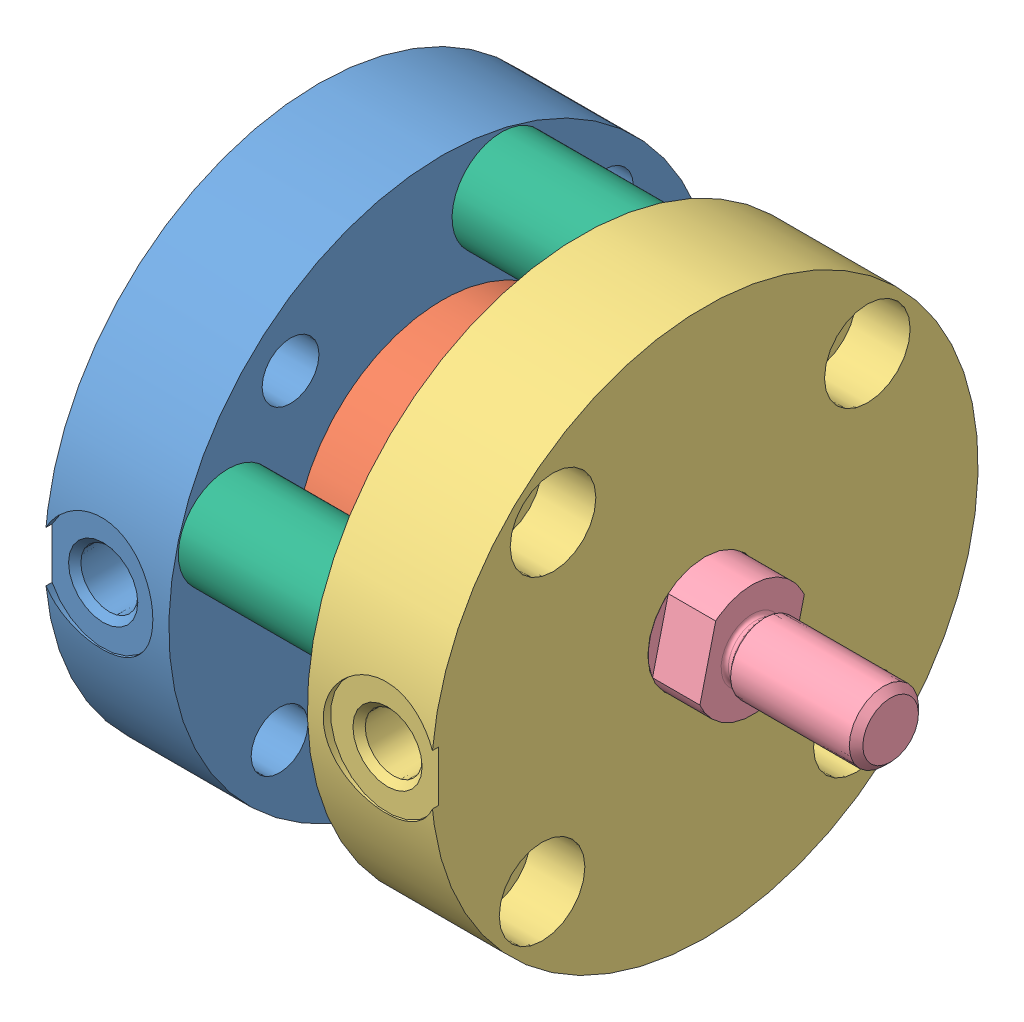
SolidWorks assembly FO-040.5-MT, configuration Default. Lengths in mm.
Overall size (40.11 38.1 38.1).
9 component instances, 6 part files, 2 mates.
Components (placement in the parent):
- _04-2-0.51-FO1_BM_heads-1: _04-2-0.51-FO1_BM_heads [Default] at (8.636 0 0) x (0 0 -1) z (0 1 0) size (38.1 8.87 38.1)
- _040.72-FO1_BM_tube-1: _040.72-FO1_BM_tube [Default] at (4.318 0 0) x (0 0 -1) z (0 -1 0) size (20.62 18.29 20.62)
- _04-1-0.51-FO1_BM_heads-1: _04-1-0.51-FO1_BM_heads [Default] at (18.288 0 0) x (0 0 -1) z (0 -1 0) size (38.1 8.87 38.1)
- _041.41.4MT-FO1_BM_rod-1: _041.41.4MT-FO1_BM_rod [Default] at (4.318 0 0) x (0 0.236027 0.971746) z (0 0.971746 -0.236027) size (7.87 35.56 7.87)
- _0.750.22-rod_part-1: _0.750.22-rod_part [Default] at (4.318 0 0) x (0 0 -1) z (-1 0 0) size (19.05 19.05 5.59)
- _040.72-FO1_BM_r-1: _040.72-FO1_BM_r [Default] at (22.606 4.1406 14.9305) x (0 0 -1) z (0 1 0) size (6.91 18.29 6.91)
- _040.72-FO1_BM_r-2: _040.72-FO1_BM_r [Default] at (22.606 14.9305 -4.1406) x (0 0 -1) z (0 1 0) size (6.91 18.29 6.91)
- _040.72-FO1_BM_r-3: _040.72-FO1_BM_r [Default] at (22.606 -4.1406 -14.9305) x (0 0 -1) z (0 1 0) size (6.91 18.29 6.91)
- _040.72-FO1_BM_r-4: _040.72-FO1_BM_r [Default] at (22.606 -14.9305 4.1406) x (0 0 -1) z (0 1 0) size (6.91 18.29 6.91)
Mates (geometry in assembly coordinates):
- Concentric3: concentric aligned: cylinder of _04-1-0.51-FO1_BM_heads-1 through (18.288 0 0) axis (1 0 0) radius 3.9624; cylinder of _041.41.4MT-FO1_BM_rod-1 through (4.318 0 0) axis (1 0 0) radius 3.937
- LimitDistance1: limit distance = 0 mm anti-aligned: plane of _04-2-0.51-FO1_BM_heads-1 through (4.318 0 0) normal (1 0 0); plane of _041.41.4MT-FO1_BM_rod-1 through (4.318 0.9292 3.8258) normal (-1 0 0)
